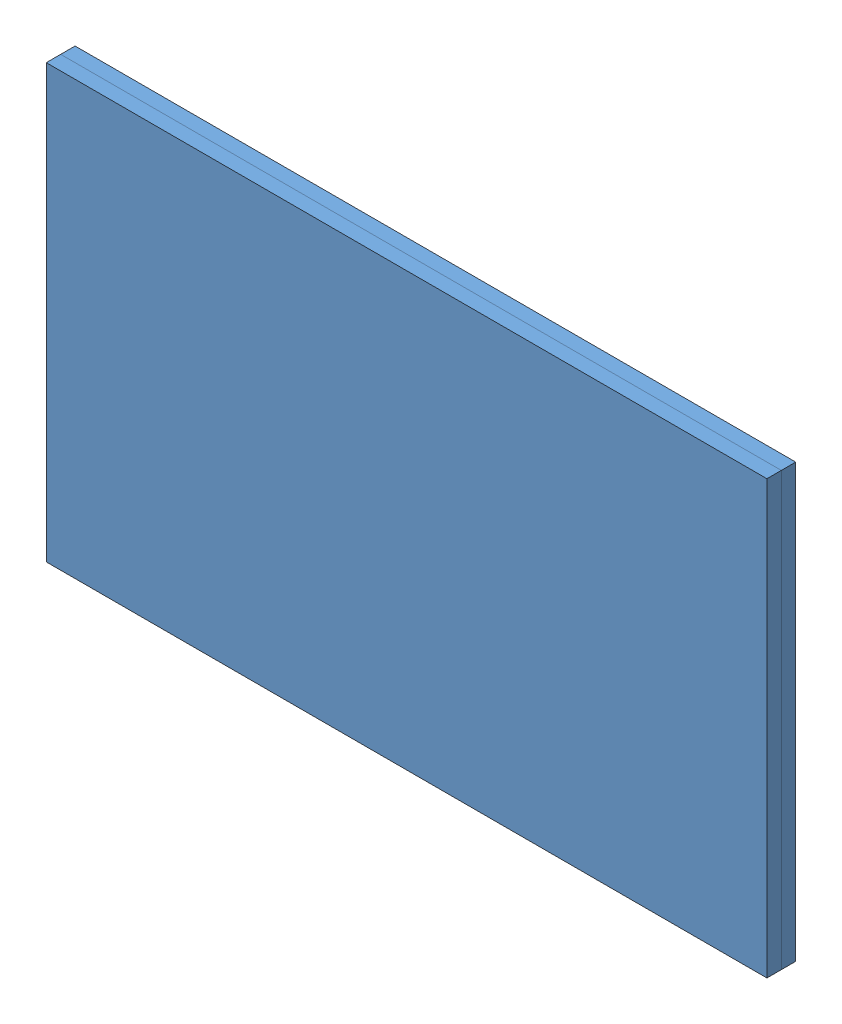
SolidWorks assembly Baugruppe2, configuration Standard. Lengths in mm.
Overall size (50 30 2).
2 component instances, 1 part files, 3 mates.
Components (placement in the parent):
- Test Teil 1-1: Test Teil 1 [Standard] at (-28.5855 -14.8051 -0.5) size (50 30 1)
- Test Teil 1-2: Test Teil 1 [Standard] at (-28.5855 -14.8051 0.5) size (50 30 1)
Mates (geometry in assembly coordinates):
- Deckungsgleich1: coincident aligned: plane of Test Teil 1-1 through (-28.5855 -14.8051 0.5) normal (-1 0 0); plane of Test Teil 1-2 through (-28.5855 -14.8051 1.5) normal (-1 0 0)
- Deckungsgleich2: coincident aligned: line of Test Teil 1-1 through (-28.5855 -14.8051 0.5) axis (1 0 0); line of Test Teil 1-2 through (-28.5855 -14.8051 0.5) axis (1 0 0)
- LimitWinkel1: limit planar angle = 3.141593 rad aligned: plane of Test Teil 1-2 through (-28.5855 15.1949 0.5) normal (0 0 -1); plane of Test Teil 1-1 through (-28.5855 15.1949 0.5) normal (0 0 1)
